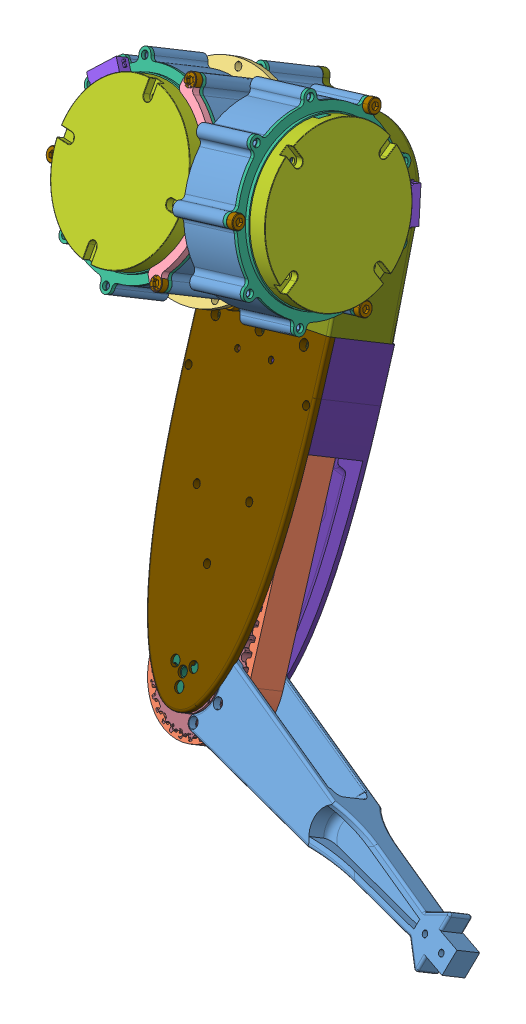
SolidWorks assembly 右后机械腿装配体, configuration 默认. Lengths in mm.
Overall size (251.73 287.49 164.5).
74 component instances, 22 part files, 38 mates.
Components (placement in the parent):
- CyberGearmotor.stp-1: CyberGearmotor.stp [默认] at (-142.9395 145.7297 202.822) x (0.962425 -0.140801 0.232192) z (-0.142242 0.466971 0.872757) size (96.28 96.17 36.5)
  - ASM0002_ASM_1_ASM.stp-1: ASM0002_ASM_1_ASM.stp [默认] at origin size (96.28 96.17 36.5)
    - ASM0002_ASM_1_ASM_1_ASM.stp-1: ASM0002_ASM_1_ASM_1_ASM.stp [默认] at origin size (96.28 96.17 36.5)
      - 0714_ASM_1_ASM_1_ASM_1_ASM.stp-1: 0714_ASM_1_ASM_1_ASM_1_ASM.stp [默认] at origin size (96.28 96.17 36.5)
        - 3_1_02_067_0003_ASM_ASM_1_ASM_1_ASM.stp-1: 3_1_02_067_0003_ASM_ASM_1_ASM_1_ASM.stp [默认] at origin size (96.28 96.17 36.5)
          - 3_1_02_067_0003_ASM_1_ASM_1_ASM_ASM.stp-1: 3_1_02_067_0003_ASM_1_ASM_1_ASM_ASM.stp [默认] at origin size (96.28 96.17 36.5)
            - 1_1_06_EB673-504_1_1_1_1_1.stp-1: 1_1_06_EB673-504_1_1_1_1_1.stp [默认] at (39.8324 39.833 -22) size (79.19 78.95 25.5)
            - 1_2_04_670601_1_1_1_1_1.stp-1: 1_2_04_670601_1_1_1_1_1.stp [默认] at (93.9161 79.9966 -44) size (37 37 4)
            - 1_1_02_EB671-500_1_1_1_1_1.stp-1: 1_1_02_EB671-500_1_1_1_1_1.stp [默认] at (93.9161 79.9966 -44.4) x (-0.960973 0.276644 0) z (0 0 1) size (33 33 8.5)
            - 1_2_04_694000_1_1_1_1_1.stp-1: 1_2_04_694000_1_1_1_1_1.stp [默认] at (93.9161 79.9966 -44.5) size (11 11 4)
            - 1_2_06_000213_1_1_1_1_1.stp-1: 1_2_06_000213_1_1_1_1_1.stp [默认] at (93.9161 79.9966 -45.5) size (38.8 36.2 1.5)
            - 1_1_31_QT-642_1_1_1_1_1.stp-1: 1_1_31_QT-642_1_1_1_1_1.stp [默认] at (93.9161 79.9966 -22) x (-0.970555 -0.24088 0) z (0 0 -1) size (79.5 79.36 6)
            - 1_1_06_EB673-502_1_1_1_1_1.stp-1: 1_1_06_EB673-502_1_1_1_1_1.stp [默认] at (93.9161 79.9966 -13) x (-0.515958 -0.856614 0) z (0 0 -1) size (63 63 8)
          - 0518_ASM_2_ASM_1_ASM_1_ASM_1_AS_ASM.stp-1: 0518_ASM_2_ASM_1_ASM_1_ASM_1_AS_ASM.stp [默认] at (93.9161 79.9966 -17.235) x (0.235897 -0.971778 0) z (0 0 1) size (15.5 11.3 5.2)
            - 12345_ASM_1_ASM_2_ASM_1_ASM_1_A_ASM.stp-1: 12345_ASM_1_ASM_2_ASM_1_ASM_1_A_ASM.stp [默认] at origin size (15.5 11.3 5.2)
              - DUANZI_1_3_1_1_1_1_1_1.stp-1: DUANZI_1_3_1_1_1_1_1_1.stp [默认] at (-0.1798 16.5474 0.4329) x (0 0 -1) z (0 1 0) size (5.2 15.5 11.3)
      - LUODING_1_1.stp-1: LUODING_1_1.stp [默认] at (119.9375 52.9941 -20.5) x (-1 0 0) z (0 1 0) size (5.68 3 5.68)
      - LUODING_1_1.stp-2: LUODING_1_1.stp [默认] at (104.2902 116.0331 -20.5) x (-1 0 0) z (0 1 0) size (5.68 3 5.68)
      - LUODING_1_1.stp-3: LUODING_1_1.stp [默认] at (57.5205 70.9626 -20.5) x (-1 0 0) z (0 1 0) size (5.68 3 5.68)
  - 0411-2_4_1_3_1.stp-1: 0411-2_4_1_3_1.stp [默认] at (93.9161 79.9964 -17.5) x (0.235904 -0.971776 0) z (0 0 1) size (58 56.68 1.62)
- 带轮-1: 带轮 [默认] at (-24.4468 170.8219 131.3671) x (-0.343989 -0.850087 0.398778) z (-0.142242 0.466971 0.872757) size (43.22 43.22 15)
- 带轮挡边-1: 带轮挡边 [默认] at (-26.5804 177.8265 144.4584) x (-0.343989 -0.850087 0.398778) z (-0.142242 0.466971 0.872757) size (50 50 4)
- 带轮挡边-2: 带轮挡边 [默认] at (-23.8778 168.9541 127.8761) x (-0.748404 0.526319 -0.403584) z (-0.142242 0.466971 0.872757) size (50 50 4)
- 膝关节带轮-1: 膝关节带轮 [默认] at (-1.5747 18.1199 216.7985) x (-0.235503 -0.872369 0.428382) z (-0.142242 0.466971 0.872757) size (43.22 43.22 23)
- 轴承-1: 轴承 [默认] at (0.6262 46.0224 223.4251) x (-0.92983 0.239281 -0.279572) z (0.142242 -0.466971 -0.872757) size (23 23 4)
- 轴承-2: 轴承 [默认] at (3.2577 37.3834 207.2791) x (0.611134 0.73503 -0.293678) z (0.142242 -0.466971 -0.872757) size (23 23 4)
- 膝关节转轴-1: 膝关节转轴 [默认] at (0.2706 47.1898 225.607) x (-0.926053 0.2486 -0.283942) z (0.142242 -0.466971 -0.872757) size (21 21 29)
- 大腿根部SLDPRT-3: 大腿根部SLDPRT [默认] at (-70.696 232.4841 116.0443) x (0.0622 0.884197 -0.462955) z (0.142242 -0.466971 -0.872757) size (94.61 80.08 30.19)
- 大腿前部-1: 大腿前部 [默认] at (-1.8386 102.8642 162.2464) x (0.97377 0.224213 0.038739) z (0.177593 -0.855375 0.486615) size (62 27.01 128.98)
- 大腿前部盖子-1: 大腿前部盖子 [默认] at (-21.6364 113.2974 187.8113) x (-0.97377 -0.224213 -0.038739) z (0.177593 -0.855375 0.486615) size (62 3.5 129)
- 小腿2-1: 小腿2 [默认] at (64.4519 33.7491 233.5195) x (0.961408 -0.144603 0.23406) z (0.235503 0.872369 -0.428382) size (141.69 21.45 28.63)
- 5m同步带1-1: 5m同步带1 [默认] at (2.0151 41.7325 213.343) x (0.142242 -0.466971 -0.872757) z (0.177593 -0.855375 0.486615) size (15 46.9 201.91)
- 连接盘-1: 连接盘 [默认] at (-33.7648 199.3725 183.8929) x (-0.075296 0.874063 -0.479942) z (-0.986964 -0.133983 -0.089167) size (80.5 13.5 80.5)
- CyberGearmotor.stp-2: CyberGearmotor.stp [默认] at (75.7649 194.8202 259.7508) x (-0.509024 0.72169 -0.469103) z (-0.142242 0.466971 0.872757) size (96.28 96.17 36.5)
  - ASM0002_ASM_1_ASM.stp-1: ASM0002_ASM_1_ASM.stp [默认] at origin size (96.28 96.17 36.5)
    - ASM0002_ASM_1_ASM_1_ASM.stp-1: ASM0002_ASM_1_ASM_1_ASM.stp [默认] at origin size (96.28 96.17 36.5)
      - 0714_ASM_1_ASM_1_ASM_1_ASM.stp-1: 0714_ASM_1_ASM_1_ASM_1_ASM.stp [默认] at origin size (96.28 96.17 36.5)
        - 3_1_02_067_0003_ASM_ASM_1_ASM_1_ASM.stp-1: 3_1_02_067_0003_ASM_ASM_1_ASM_1_ASM.stp [默认] at origin size (96.28 96.17 36.5)
          - 3_1_02_067_0003_ASM_1_ASM_1_ASM_ASM.stp-1: 3_1_02_067_0003_ASM_1_ASM_1_ASM_ASM.stp [默认] at origin size (96.28 96.17 36.5)
            - 1_1_06_EB673-504_1_1_1_1_1.stp-1: 1_1_06_EB673-504_1_1_1_1_1.stp [默认] at (39.8324 39.833 -22) size (79.19 78.95 25.5)
            - 1_2_04_670601_1_1_1_1_1.stp-1: 1_2_04_670601_1_1_1_1_1.stp [默认] at (93.9161 79.9966 -44) size (37 37 4)
            - 1_1_02_EB671-500_1_1_1_1_1.stp-1: 1_1_02_EB671-500_1_1_1_1_1.stp [默认] at (93.9161 79.9966 -44.4) x (-0.960973 0.276644 0) z (0 0 1) size (33 33 8.5)
            - 1_2_04_694000_1_1_1_1_1.stp-1: 1_2_04_694000_1_1_1_1_1.stp [默认] at (93.9161 79.9966 -44.5) size (11 11 4)
            - 1_2_06_000213_1_1_1_1_1.stp-1: 1_2_06_000213_1_1_1_1_1.stp [默认] at (93.9161 79.9966 -45.5) size (38.8 36.2 1.5)
            - 1_1_31_QT-642_1_1_1_1_1.stp-1: 1_1_31_QT-642_1_1_1_1_1.stp [默认] at (93.9161 79.9966 -22) x (-0.970555 -0.24088 0) z (0 0 -1) size (79.5 79.36 6)
            - 1_1_06_EB673-502_1_1_1_1_1.stp-1: 1_1_06_EB673-502_1_1_1_1_1.stp [默认] at (93.9161 79.9966 -13) x (-0.515958 -0.856614 0) z (0 0 -1) size (63 63 8)
          - 0518_ASM_2_ASM_1_ASM_1_ASM_1_AS_ASM.stp-1: 0518_ASM_2_ASM_1_ASM_1_ASM_1_AS_ASM.stp [默认] at (93.9161 79.9966 -17.235) x (0.235897 -0.971778 0) z (0 0 1) size (15.5 11.3 5.2)
            - 12345_ASM_1_ASM_2_ASM_1_ASM_1_A_ASM.stp-1: 12345_ASM_1_ASM_2_ASM_1_ASM_1_A_ASM.stp [默认] at origin size (15.5 11.3 5.2)
              - DUANZI_1_3_1_1_1_1_1_1.stp-1: DUANZI_1_3_1_1_1_1_1_1.stp [默认] at (-0.1798 16.5474 0.4329) x (0 0 -1) z (0 1 0) size (5.2 15.5 11.3)
      - LUODING_1_1.stp-1: LUODING_1_1.stp [默认] at (119.9375 52.9941 -20.5) x (-1 0 0) z (0 1 0) size (5.68 3 5.68)
      - LUODING_1_1.stp-2: LUODING_1_1.stp [默认] at (104.2902 116.0331 -20.5) x (-1 0 0) z (0 1 0) size (5.68 3 5.68)
      - LUODING_1_1.stp-3: LUODING_1_1.stp [默认] at (57.5205 70.9626 -20.5) x (-1 0 0) z (0 1 0) size (5.68 3 5.68)
  - 0411-2_4_1_3_1.stp-1: 0411-2_4_1_3_1.stp [默认] at (93.9161 79.9964 -17.5) x (0.235904 -0.971776 0) z (0 0 1) size (58 56.68 1.62)
- 肩关节连接器-1: 肩关节连接器 [默认] at (-36.3841 260.8063 150.3665) x (-0.509046 0.721677 -0.4691) z (0.848905 0.510999 -0.135057) size (67.92 36.71 40.7)
- CyberGearmotor.stp-3: CyberGearmotor.stp [默认] at (56.3683 218.9179 320.1116) x (0.161386 -0.529819 -0.832614) z (0.956605 0.291387 0) size (96.28 96.17 36.5)
  - ASM0002_ASM_1_ASM.stp-1: ASM0002_ASM_1_ASM.stp [默认] at origin size (96.28 96.17 36.5)
    - ASM0002_ASM_1_ASM_1_ASM.stp-1: ASM0002_ASM_1_ASM_1_ASM.stp [默认] at origin size (96.28 96.17 36.5)
      - 0714_ASM_1_ASM_1_ASM_1_ASM.stp-1: 0714_ASM_1_ASM_1_ASM_1_ASM.stp [默认] at origin size (96.28 96.17 36.5)
        - 3_1_02_067_0003_ASM_ASM_1_ASM_1_ASM.stp-1: 3_1_02_067_0003_ASM_ASM_1_ASM_1_ASM.stp [默认] at origin size (96.28 96.17 36.5)
          - 3_1_02_067_0003_ASM_1_ASM_1_ASM_ASM.stp-1: 3_1_02_067_0003_ASM_1_ASM_1_ASM_ASM.stp [默认] at origin size (96.28 96.17 36.5)
            - 1_1_06_EB673-504_1_1_1_1_1.stp-1: 1_1_06_EB673-504_1_1_1_1_1.stp [默认] at (39.8324 39.833 -22) size (79.19 78.95 25.5)
            - 1_2_04_670601_1_1_1_1_1.stp-1: 1_2_04_670601_1_1_1_1_1.stp [默认] at (93.9161 79.9966 -44) size (37 37 4)
            - 1_1_02_EB671-500_1_1_1_1_1.stp-1: 1_1_02_EB671-500_1_1_1_1_1.stp [默认] at (93.9161 79.9966 -44.4) x (-0.960973 0.276644 0) z (0 0 1) size (33 33 8.5)
            - 1_2_04_694000_1_1_1_1_1.stp-1: 1_2_04_694000_1_1_1_1_1.stp [默认] at (93.9161 79.9966 -44.5) size (11 11 4)
            - 1_2_06_000213_1_1_1_1_1.stp-1: 1_2_06_000213_1_1_1_1_1.stp [默认] at (93.9161 79.9966 -45.5) size (38.8 36.2 1.5)
            - 1_1_31_QT-642_1_1_1_1_1.stp-1: 1_1_31_QT-642_1_1_1_1_1.stp [默认] at (93.9161 79.9966 -22) x (-0.970555 -0.24088 0) z (0 0 -1) size (79.5 79.36 6)
            - 1_1_06_EB673-502_1_1_1_1_1.stp-1: 1_1_06_EB673-502_1_1_1_1_1.stp [默认] at (93.9161 79.9966 -13) x (-0.515958 -0.856614 0) z (0 0 -1) size (63 63 8)
          - 0518_ASM_2_ASM_1_ASM_1_ASM_1_AS_ASM.stp-1: 0518_ASM_2_ASM_1_ASM_1_ASM_1_AS_ASM.stp [默认] at (93.9161 79.9966 -17.235) x (0.235897 -0.971778 0) z (0 0 1) size (15.5 11.3 5.2)
            - 12345_ASM_1_ASM_2_ASM_1_ASM_1_A_ASM.stp-1: 12345_ASM_1_ASM_2_ASM_1_ASM_1_A_ASM.stp [默认] at origin size (15.5 11.3 5.2)
              - DUANZI_1_3_1_1_1_1_1_1.stp-1: DUANZI_1_3_1_1_1_1_1_1.stp [默认] at (-0.1798 16.5474 0.4329) x (0 0 -1) z (0 1 0) size (5.2 15.5 11.3)
      - LUODING_1_1.stp-1: LUODING_1_1.stp [默认] at (119.9375 52.9941 -20.5) x (-1 0 0) z (0 1 0) size (5.68 3 5.68)
      - LUODING_1_1.stp-2: LUODING_1_1.stp [默认] at (104.2902 116.0331 -20.5) x (-1 0 0) z (0 1 0) size (5.68 3 5.68)
      - LUODING_1_1.stp-3: LUODING_1_1.stp [默认] at (57.5205 70.9626 -20.5) x (-1 0 0) z (0 1 0) size (5.68 3 5.68)
  - 0411-2_4_1_3_1.stp-1: 0411-2_4_1_3_1.stp [默认] at (93.9161 79.9964 -17.5) x (0.235904 -0.971776 0) z (0 0 1) size (58 56.68 1.62)
Mates (geometry in assembly coordinates):
- 同心1: concentric aligned: cylinder of CyberGearmotor.stp-1/ASM0002_ASM_1_ASM.stp-1/ASM0002_ASM_1_ASM_1_ASM.stp-1/0714_ASM_1_ASM_1_ASM_1_ASM.stp-1/3_1_02_067_0003_ASM_ASM_1_ASM_1_ASM.stp-1/3_1_02_067_0003_ASM_1_ASM_1_ASM_ASM.stp-1/1_1_02_EB671-500_1_1_1_1_1.stp-1 through (-27.7326 181.609 151.5278) axis (0.142242 -0.466971 -0.872757) radius 16.5; cylinder of 带轮挡边-1 through (-27.1494 179.6944 147.9495) axis (0.142242 -0.466971 -0.872757) radius 25
- 重合1: coincident anti-aligned: plane of CyberGearmotor.stp-1/ASM0002_ASM_1_ASM.stp-1/ASM0002_ASM_1_ASM_1_ASM.stp-1/0714_ASM_1_ASM_1_ASM_1_ASM.stp-1/3_1_02_067_0003_ASM_ASM_1_ASM_1_ASM.stp-1/3_1_02_067_0003_ASM_1_ASM_1_ASM_ASM.stp-1/1_1_02_EB671-500_1_1_1_1_1.stp-1 through (-27.1494 179.6944 147.9495) normal (0.142242 -0.466971 -0.872757); plane of 带轮挡边-1 through (-27.1494 179.6944 147.9495) normal (-0.142242 0.466971 0.872757)
- 重合4: coincident anti-aligned: plane of 带轮-1 through (-7.9571 170.432 151.4502) normal (-0.142242 0.466971 0.872757); plane of 带轮挡边-1 through (-26.5804 177.8265 144.4584) normal (0.142242 -0.466971 -0.872757)
- 同心12: concentric aligned: cylinder of CyberGearmotor.stp-1/ASM0002_ASM_1_ASM.stp-1/ASM0002_ASM_1_ASM_1_ASM.stp-1/0714_ASM_1_ASM_1_ASM_1_ASM.stp-1/3_1_02_067_0003_ASM_ASM_1_ASM_1_ASM.stp-1/3_1_02_067_0003_ASM_1_ASM_1_ASM_ASM.stp-1/1_1_02_EB671-500_1_1_1_1_1.stp-1 through (-27.7326 181.609 151.5278) axis (0.142242 -0.466971 -0.872757) radius 16.5; cylinder of 带轮挡边-2 through (-24.4468 170.8219 131.3671) axis (0.142242 -0.466971 -0.872757) radius 25
- 重合5: coincident anti-aligned: plane of 带轮-1 through (-5.8235 163.4274 138.3588) normal (0.142242 -0.466971 -0.872757); plane of 带轮挡边-2 through (-24.4468 170.8219 131.3671) normal (-0.142242 0.466971 0.872757)
- 同心20: concentric aligned: cylinder of 轴承-1 through (1.1952 44.1545 219.934) axis (-0.142242 0.466971 0.872757) radius 8.5; cylinder of 膝关节转轴-1 through (4.2534 34.1146 201.1698) axis (-0.142242 0.466971 0.872757) radius 8.5
- 重合12: coincident anti-aligned: plane of CyberGearmotor.stp-1/ASM0002_ASM_1_ASM.stp-1/ASM0002_ASM_1_ASM_1_ASM.stp-1/0714_ASM_1_ASM_1_ASM_1_ASM.stp-1/3_1_02_067_0003_ASM_ASM_1_ASM_1_ASM.stp-1/3_1_02_067_0003_ASM_1_ASM_1_ASM_ASM.stp-1/1_1_06_EB673-504_1_1_1_1_1.stp-1 through (-27.3028 180.4312 150.9676) normal (0.142242 -0.466971 -0.872757); plane of 大腿根部SLDPRT-3 through (-70.696 232.4841 116.0443) normal (-0.142242 0.466971 0.872757)
- 重合17: coincident anti-aligned: plane of 大腿根部SLDPRT-3 through (-45.8259 118.5874 150.102) normal (0.142242 -0.466971 -0.872757); plane of 大腿前部-1 through (-2.2654 104.2651 164.8647) normal (-0.142242 0.466971 0.872757)
- 重合18: coincident anti-aligned: plane of 大腿根部SLDPRT-3 through (-51.4424 139.7494 168.8003) normal (0.177593 -0.855375 0.486615); plane of 大腿前部-1 through (-8.8666 136.06 146.7768) normal (-0.177593 0.855375 -0.486615)
- 重合21: coincident anti-aligned: plane of 大腿根部SLDPRT-3 through (8.5691 144.6045 175.9832) normal (0.97377 0.224213 0.038739); plane of 大腿前部-1 through (13.8211 119.9624 186.5866) normal (-0.97377 -0.224213 -0.038739)
- 同心32: concentric anti-aligned: cylinder of 膝关节转轴-1 through (4.2534 34.1146 201.1698) axis (-0.142242 0.466971 0.872757) radius 8.5; cylinder of 大腿前部-1 through (3.9689 35.0486 202.9153) axis (0.142242 -0.466971 -0.872757) radius 8.5
- 重合23: coincident aligned: plane of 膝关节转轴-1 through (4.3956 33.6477 200.297) normal (0.142242 -0.466971 -0.872757); plane of 大腿前部-1 through (-1.8386 102.8642 162.2464) normal (0.142242 -0.466971 -0.872757)
- 重合32: coincident anti-aligned: plane of 带轮挡边-1 through (-26.5804 177.8265 144.4584) normal (0.142242 -0.466971 -0.872757); plane of 5m同步带1-1 through (-18.1844 40.8295 219.1275) normal (-0.142242 0.466971 0.872757)
- 同心44: concentric aligned: cylinder of 带轮挡边-1 through (-27.1494 179.6944 147.9495) axis (0.142242 -0.466971 -0.872757) radius 25; cylinder of 5m同步带1-1 through (-25.5136 174.3242 137.9128) axis (0.142242 -0.466971 -0.872757) radius 23.448
- 同心47: concentric anti-aligned: cylinder of 膝关节带轮-1 through (1.1241 44.388 220.3704) axis (0.142242 -0.466971 -0.872757) radius 10.5; cylinder of 膝关节转轴-1 through (4.2534 34.1146 201.1698) axis (-0.142242 0.466971 0.872757) radius 8.5
- 重合36: coincident anti-aligned: plane of 膝关节带轮-1 through (22.8305 31.9962 213.3515) normal (0.142242 -0.466971 -0.872757); plane of 轴承-2 through (3.2577 37.3834 207.2791) normal (-0.142242 0.466971 0.872757)
- 重合38: coincident anti-aligned: plane of 带轮-1 through (-7.9571 170.432 151.4502) normal (-0.142242 0.466971 0.872757); plane of 带轮挡边-1 through (-26.5804 177.8265 144.4584) normal (0.142242 -0.466971 -0.872757)
- 重合39: coincident aligned: plane of 带轮-1 through (-5.8235 163.4274 138.3588) normal (0.142242 -0.466971 -0.872757); plane of 膝关节带轮-1 through (22.8305 31.9962 213.3515) normal (0.142242 -0.466971 -0.872757)
- 重合41: coincident anti-aligned: plane of 膝关节带轮-1 through (1.252 44.1493 219.9461) normal (-0.142242 0.466971 0.872757); plane of 轴承-1 through (1.1952 44.1545 219.934) normal (0.142242 -0.466971 -0.872757)
- 重合42: coincident anti-aligned: plane of 膝关节带轮-1 through (22.8305 31.9962 213.3515) normal (0.142242 -0.466971 -0.872757); plane of 小腿2-1 through (66.2299 27.912 222.61) normal (-0.142242 0.466971 0.872757)
- 同心50: concentric aligned: cylinder of 膝关节带轮-1 through (14.6656 52.6217 218.1719) axis (-0.142242 0.466971 0.872757) radius 1.65; cylinder of 小腿2-1 through (21.3509 30.6741 177.1523) axis (-0.142242 0.466971 0.872757) radius 2.1
- 同心51: concentric aligned: cylinder of 膝关节带轮-1 through (16.5066 42.0744 224.1154) axis (-0.142242 0.466971 0.872757) radius 1.65; cylinder of 小腿2-1 through (23.192 20.1267 183.0958) axis (-0.142242 0.466971 0.872757) radius 2.1
- 同心53: concentric aligned: circle of 轴承-2; cylinder of 膝关节转轴-1 through (0.9818 44.855 221.2432) axis (0.142242 -0.466971 -0.872757) radius 7
- 重合44: coincident anti-aligned: plane of 大腿根部SLDPRT-3 through (-49.2397 129.7947 171.0482) normal (-0.142242 0.466971 0.872757); plane of 大腿前部盖子-1 through (-21.2097 111.8965 185.193) normal (0.142242 -0.466971 -0.872757)
- 同心54: concentric anti-aligned: cylinder of 大腿根部SLDPRT-3 through (-36.1931 125.2867 148.0875) axis (0.142242 -0.466971 -0.872757) radius 1.65; cylinder of 大腿前部盖子-1 through (-39.6069 136.4941 169.0336) axis (-0.142242 0.466971 0.872757) radius 2.1
- 同心55: concentric anti-aligned: cylinder of 大腿根部SLDPRT-3 through (4.7053 134.7037 149.7145) axis (0.142242 -0.466971 -0.872757) radius 1.65; cylinder of 大腿前部盖子-1 through (1.2915 145.911 170.6607) axis (-0.142242 0.466971 0.872757) radius 2.1
- 重合45: coincident anti-aligned: plane of CyberGearmotor.stp-1/ASM0002_ASM_1_ASM.stp-1/ASM0002_ASM_1_ASM_1_ASM.stp-1/0714_ASM_1_ASM_1_ASM_1_ASM.stp-1/3_1_02_067_0003_ASM_ASM_1_ASM_1_ASM.stp-1/3_1_02_067_0003_ASM_1_ASM_1_ASM_ASM.stp-1/1_1_06_EB673-502_1_1_1_1_1.stp-1 through (-32.3412 196.7389 179.8051) normal (-0.142242 0.466971 0.872757); plane of 连接盘-1 through (-33.0536 197.0377 179.5291) normal (0.142242 -0.466971 -0.872757)
- 同心56: concentric aligned: cylinder of CyberGearmotor.stp-1/ASM0002_ASM_1_ASM.stp-1/ASM0002_ASM_1_ASM_1_ASM.stp-1/0714_ASM_1_ASM_1_ASM_1_ASM.stp-1/3_1_02_067_0003_ASM_ASM_1_ASM_1_ASM.stp-1/3_1_02_067_0003_ASM_1_ASM_1_ASM_ASM.stp-1/1_1_06_EB673-502_1_1_1_1_1.stp-1 through (-31.2033 193.0031 172.8231) axis (-0.142242 0.466971 0.872757) radius 31.5; cylinder of 连接盘-1 through (-32.3412 196.7389 179.8051) axis (-0.142242 0.466971 0.872757) radius 40.25
- 同心57: concentric aligned: cylinder of CyberGearmotor.stp-1/ASM0002_ASM_1_ASM.stp-1/ASM0002_ASM_1_ASM_1_ASM.stp-1/0714_ASM_1_ASM_1_ASM_1_ASM.stp-1/3_1_02_067_0003_ASM_ASM_1_ASM_1_ASM.stp-1/3_1_02_067_0003_ASM_1_ASM_1_ASM_ASM.stp-1/1_1_31_QT-642_1_1_1_1_1.stp-1 through (-59.3893 169.4135 180.2781) axis (-0.142242 0.466971 0.872757) radius 1.55; cylinder of 连接盘-1 through (-60.5984 173.3827 187.6965) axis (-0.142242 0.466971 0.872757) radius 1.6
- 同心61: concentric aligned: cylinder of CyberGearmotor.stp-1/ASM0002_ASM_1_ASM.stp-1/ASM0002_ASM_1_ASM_1_ASM.stp-1/0714_ASM_1_ASM_1_ASM_1_ASM.stp-1/3_1_02_067_0003_ASM_ASM_1_ASM_1_ASM.stp-1/3_1_02_067_0003_ASM_1_ASM_1_ASM_ASM.stp-1/1_1_06_EB673-502_1_1_1_1_1.stp-1 through (-31.2033 193.0031 172.8231) axis (-0.142242 0.466971 0.872757) radius 31.5; cylinder of CyberGearmotor.stp-2/ASM0002_ASM_1_ASM.stp-1/ASM0002_ASM_1_ASM_1_ASM.stp-1/0714_ASM_1_ASM_1_ASM_1_ASM.stp-1/3_1_02_067_0003_ASM_ASM_1_ASM_1_ASM.stp-1/3_1_02_067_0003_ASM_1_ASM_1_ASM_ASM.stp-1/1_1_06_EB673-502_1_1_1_1_1.stp-1 through (-37.1063 212.3824 209.0425) axis (-0.142242 0.466971 0.872757) radius 31.5
- 重合48: coincident anti-aligned: plane of 连接盘-1 through (-33.7648 199.3725 183.8929) normal (-0.142242 0.466971 0.872757); plane of CyberGearmotor.stp-2/ASM0002_ASM_1_ASM.stp-1/ASM0002_ASM_1_ASM_1_ASM.stp-1/0714_ASM_1_ASM_1_ASM_1_ASM.stp-1/3_1_02_067_0003_ASM_ASM_1_ASM_1_ASM.stp-1/3_1_02_067_0003_ASM_1_ASM_1_ASM_ASM.stp-1/1_1_02_EB671-500_1_1_1_1_1.stp-1 through (-33.0524 199.0737 184.1689) normal (0.142242 -0.466971 -0.872757)
- 同心70: concentric anti-aligned: cylinder of CyberGearmotor.stp-2/ASM0002_ASM_1_ASM.stp-1/ASM0002_ASM_1_ASM_1_ASM.stp-1/0714_ASM_1_ASM_1_ASM_1_ASM.stp-1/3_1_02_067_0003_ASM_ASM_1_ASM_1_ASM.stp-1/3_1_02_067_0003_ASM_1_ASM_1_ASM_ASM.stp-1/1_1_31_QT-642_1_1_1_1_1.stp-1 through (-37.0352 212.1489 208.6061) axis (-0.142242 0.466971 0.872757) radius 32; cylinder of 肩关节连接器-1 through (-37.4619 213.5498 211.2244) axis (0.142242 -0.466971 -0.872757) radius 32
- 重合51: coincident anti-aligned: plane of CyberGearmotor.stp-2/ASM0002_ASM_1_ASM.stp-1/ASM0002_ASM_1_ASM_1_ASM.stp-1/0714_ASM_1_ASM_1_ASM_1_ASM.stp-1/3_1_02_067_0003_ASM_ASM_1_ASM_1_ASM.stp-1/3_1_02_067_0003_ASM_1_ASM_1_ASM_ASM.stp-1/1_1_31_QT-642_1_1_1_1_1.stp-1 through (-37.0352 212.1489 208.6061) normal (-0.142242 0.466971 0.872757); plane of 肩关节连接器-1 through (-40.3953 273.9749 174.9783) normal (0.142242 -0.466971 -0.872757)
- 同心71: concentric aligned: cylinder of CyberGearmotor.stp-2/ASM0002_ASM_1_ASM.stp-1/ASM0002_ASM_1_ASM_1_ASM.stp-1/0714_ASM_1_ASM_1_ASM_1_ASM.stp-1/3_1_02_067_0003_ASM_ASM_1_ASM_1_ASM.stp-1/3_1_02_067_0003_ASM_1_ASM_1_ASM_ASM.stp-1/1_1_06_EB673-504_1_1_1_1_1.stp-1 through (0.0823 211.2279 213.9681) axis (0.142242 -0.466971 -0.872757) radius 1.25; cylinder of 肩关节连接器-1 through (-3.5918 223.2898 236.5114) axis (0.142242 -0.466971 -0.872757) radius 1.6
- 重合52: coincident anti-aligned: plane of 肩关节连接器-1 through (-9.5784 268.9715 150.3665) normal (0.956605 0.291387 0); plane of CyberGearmotor.stp-3/ASM0002_ASM_1_ASM.stp-1/ASM0002_ASM_1_ASM_1_ASM.stp-1/0714_ASM_1_ASM_1_ASM_1_ASM.stp-1/3_1_02_067_0003_ASM_ASM_1_ASM_1_ASM.stp-1/3_1_02_067_0003_ASM_1_ASM_1_ASM_ASM.stp-1/1_1_02_EB671-500_1_1_1_1_1.stp-1 through (5.7214 218.743 197.6094) normal (-0.956605 -0.291387 0)
- 同心72: concentric anti-aligned: cylinder of 肩关节连接器-1 through (-37.8855 205.4601 197.6094) axis (0.956605 0.291387 0) radius 21; cylinder of CyberGearmotor.stp-3/ASM0002_ASM_1_ASM.stp-1/ASM0002_ASM_1_ASM_1_ASM.stp-1/0714_ASM_1_ASM_1_ASM_1_ASM.stp-1/3_1_02_067_0003_ASM_ASM_1_ASM_1_ASM.stp-1/3_1_02_067_0003_ASM_1_ASM_1_ASM_ASM.stp-1/1_1_02_EB671-500_1_1_1_1_1.stp-1 through (9.6435 219.9377 197.6094) axis (-0.956605 -0.291387 0) radius 16.5
- 同心87: concentric aligned: cylinder of CyberGearmotor.stp-1/ASM0002_ASM_1_ASM.stp-1/ASM0002_ASM_1_ASM_1_ASM.stp-1/0714_ASM_1_ASM_1_ASM_1_ASM.stp-1/3_1_02_067_0003_ASM_ASM_1_ASM_1_ASM.stp-1/3_1_02_067_0003_ASM_1_ASM_1_ASM_ASM.stp-1/1_1_06_EB673-504_1_1_1_1_1.stp-1 through (-27.269 180.0871 148.6835) axis (-0.142242 0.466971 0.872757) radius 21.5; cylinder of 大腿根部SLDPRT-3 through (-23.3089 167.0862 124.385) axis (-0.142242 0.466971 0.872757) radius 29
- 平行1: parallel aligned: plane of 大腿前部-1 through (20.1563 109.4277 165.7567) normal (0.97377 0.224213 0.038739); plane of 5m同步带1-1 through (-3.7475 183.0838 145.3668) normal (0.97377 0.224213 0.038739)
